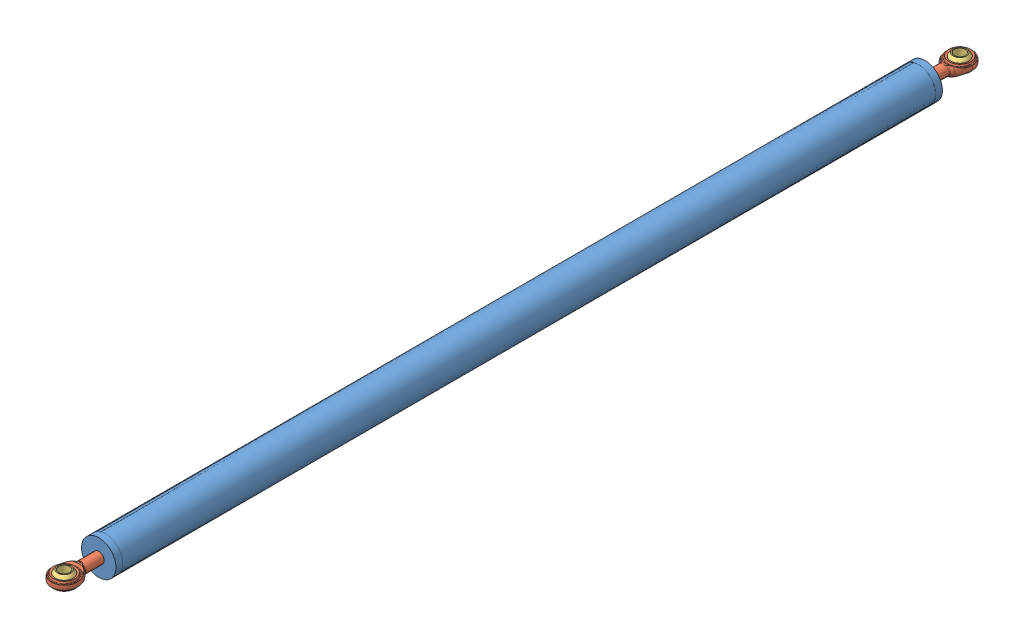
SolidWorks assembly Montagem_Haste, configuration Valor predeterminado. Lengths in mm.
Overall size (69.56 69.56 1361.51).
7 component instances, 3 part files, 5 mates.
Components (placement in the parent):
- Haste_1m-1: Haste_1m [Valor predeterminado] at (0 0 -1195) x (0.861383 0.507957 0) z (0.507957 -0.861383 0) size (50.8 1220 50.8)
- 20150831-142919-79084130-1: 20150831-142919-79084130 [Valor predeterminado] at origin size (39.51 38 85.75)
  - PRODUCT_NAME_1-1: PRODUCT_NAME_1 [Valor predeterminado] at origin size (39.51 38 85.75)
  - PRODUCT_NAME_2-1: PRODUCT_NAME_2 [Valor predeterminado] at origin size (28.58 28.58 28.58)
- 20150831-142919-79084130-2: 20150831-142919-79084130 [Valor predeterminado] at (0 0 -1190) x (-1 0 0) z (0 0 -1) size (39.51 38 85.75)
  - PRODUCT_NAME_1-1: PRODUCT_NAME_1 [Valor predeterminado] at origin size (39.51 38 85.75)
  - PRODUCT_NAME_2-1: PRODUCT_NAME_2 [Valor predeterminado] at origin size (28.58 28.58 28.58)
Mates (geometry in assembly coordinates):
- Concêntrico4: concentric aligned: cylinder of 20150831-142919-79084130-1/PRODUCT_NAME_1-1 through (0 0 20.508) axis (0 0 -1) radius 8; cylinder of Haste_1m-1 through (0 0 5) axis (0 0 -1) radius 25.4
- Distância1: distance = 15 mm anti-aligned: plane of Haste_1m-1 through (21.8791 12.9021 15) normal (0 0 1); plane of 20150831-142919-79084130-1/PRODUCT_NAME_1-1 through (3.492 0 0) normal (0 0 -1)
- Concêntrico5: concentric anti-aligned: cylinder of Haste_1m-1 through (0 0 -1195) axis (0 0 -1) radius 8; cylinder of 20150831-142919-79084130-2/PRODUCT_NAME_1-1 through (0 0 -1210.5079) axis (0 0 1) radius 8
- Distância2: distance = 15 mm anti-aligned: plane of 20150831-142919-79084130-2/PRODUCT_NAME_1-1 through (-3.492 0 -1190) normal (0 0 1); plane of Haste_1m-1 through (21.8791 12.9021 -1205) normal (0 0 -1)
- Coincidente3: coincident aligned: plane of 20150831-142919-79084130-1/PRODUCT_NAME_2-1 through (0 10.5 66) normal (0 1 0); plane of 20150831-142919-79084130-2/PRODUCT_NAME_2-1 through (0 10.5 -1256) normal (0 1 0)
